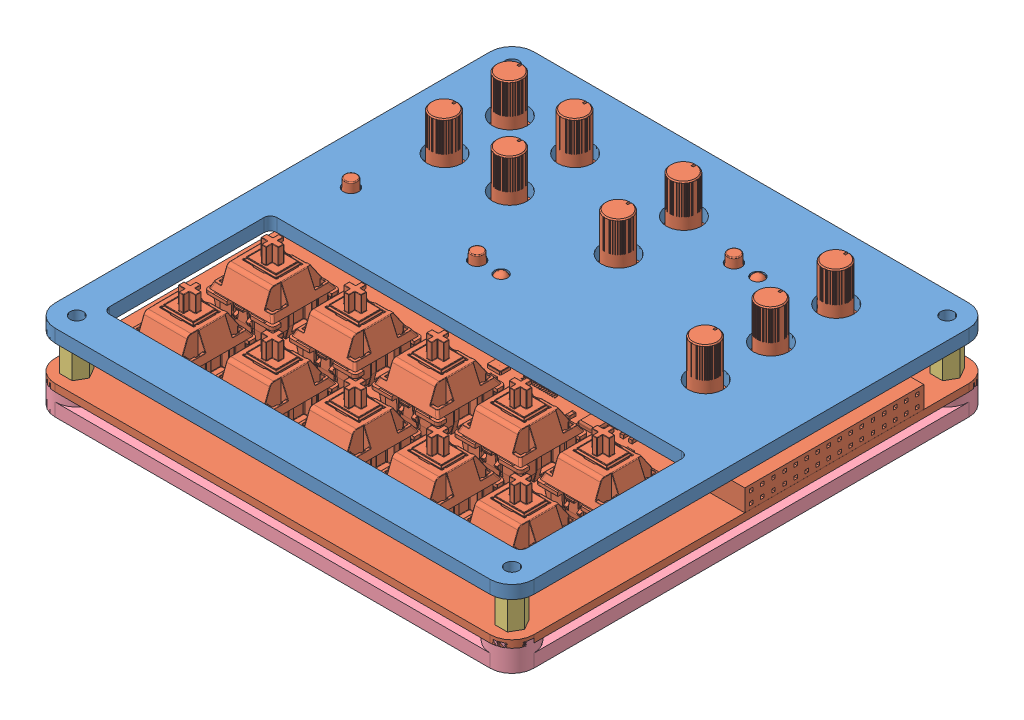
SolidWorks assembly Assembly, configuration Default. Lengths in mm.
Overall size (110.05 40 111.55).
7 component instances, 4 part files, 8 mates.
Components (placement in the parent):
- Top Plate-1: Top Plate [Default] at origin size (110 3 110)
- PCBA-1: PCBA [Default] at (-155 -8 155) x (1 0 0) z (0 1 0) size (110.05 111.55 40)
- Hex Spacer-1: Hex Spacer [Default] at (-50 -8 -50) size (5.77 8 5)
- Hex Spacer-2: Hex Spacer [Default] at (-50 -8 50) size (5.77 8 5)
- Hex Spacer-3: Hex Spacer [Default] at (50 -8 50) size (5.77 8 5)
- Hex Spacer-4: Hex Spacer [Default] at (50 -8 -50) size (5.77 8 5)
- Bottom Plate-1: Bottom Plate [Default] at (0 -14.6914 0) size (110 6 110)
Mates (geometry in assembly coordinates):
- Concentric4: concentric aligned: circle of Top Plate-1; circle of Hex Spacer-1
- Coincident6: coincident anti-aligned: plane of Top Plate-1 through (0 0 0) normal (0 -1 0); plane of Hex Spacer-1 through (-50 0 -50) normal (0 1 0)
- Concentric5: concentric aligned: circle of Top Plate-1; circle of Hex Spacer-2
- Coincident8: coincident anti-aligned: plane of Top Plate-1 through (0 0 0) normal (0 -1 0); plane of Hex Spacer-2 through (-50 0 50) normal (0 1 0)
- Concentric6: concentric aligned: circle of Top Plate-1; circle of Hex Spacer-3
- Coincident9: coincident anti-aligned: plane of Top Plate-1 through (0 0 0) normal (0 -1 0); plane of Hex Spacer-3 through (50 0 50) normal (0 1 0)
- Concentric7: concentric aligned: circle of Top Plate-1; circle of Hex Spacer-4
- Coincident10: coincident anti-aligned: plane of Top Plate-1 through (0 0 0) normal (0 -1 0); plane of Hex Spacer-4 through (50 0 -50) normal (0 1 0)
